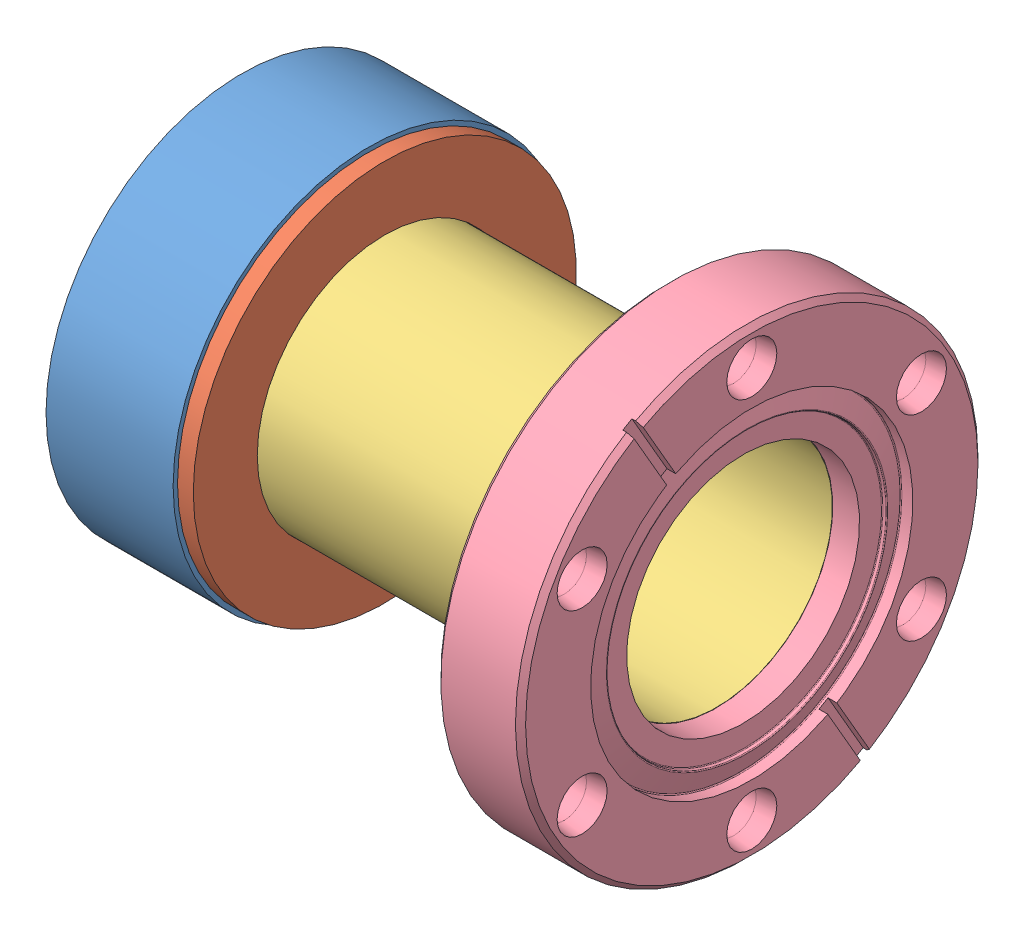
SolidWorks assembly 420033, configuration Default. Lengths in mm.
Overall size (76.43 94.72 94.72).
4 component instances, 4 part files, 7 mates.
Components (placement in the parent):
- 042250-1: 042250 [Default] at (5.3879 29.1211 49.8099) size (19.05 58.72 58.72)
- 942003-1: 942003 [Default] at (24.4379 29.1211 49.8099) x (0 0 -1) z (1 0 0) size (57.4 57.4 2.36)
- 942005-1: 942005 [Default] at (76.5079 29.1211 49.8099) x (0 -0.062024 0.998075) z (-1 0 0) size (38.1 38.1 52.07)
- 110014-REV.A-1: 110014-REV.A [Default] at (69.1165 29.1211 49.8099) x (0 0.866025 -0.5) z (1 0 0) size (69.34 69.34 12.7)
Mates (geometry in assembly coordinates):
- Concentric1: concentric anti-aligned: circle of 042250-1; circle of 942003-1
- Coincident1: coincident anti-aligned: plane of 042250-1 through (24.4379 29.1211 49.8099) normal (1 0 0); plane of 942003-1 through (24.4379 29.1211 49.8099) normal (-1 0 0)
- Concentric2: concentric anti-aligned: cylinder of 942003-1 through (26.8001 29.1211 49.8099) axis (-1 0 0) radius 19.1135; cylinder of 942005-1 through (24.4379 29.1211 49.8099) axis (1 0 0) radius 19.05
- Coincident3: coincident aligned: plane of 942003-1 through (24.4379 29.1211 49.8099) normal (-1 0 0); plane of 942005-1 through (24.4379 29.1211 49.8099) normal (-1 0 0)
- Concentric3: concentric anti-aligned: cylinder of 942005-1 through (24.4379 29.1211 49.8099) axis (1 0 0) radius 19.05; cylinder of 110014-REV.A-1 through (69.1165 29.1211 49.8099) axis (-1 0 0) radius 19.177
- Coincident4: coincident anti-aligned: plane of 942005-1 through (76.5079 29.1211 49.8099) normal (1 0 0); plane of 110014-REV.A-1 through (76.5079 48.2981 49.8099) normal (-1 0 0)
- Angle1: planar angle = 0.523599 rad aligned: plane of 110014-REV.A-1 through (69.1165 29.1211 49.8099) normal (0 0.5 0.866025)
